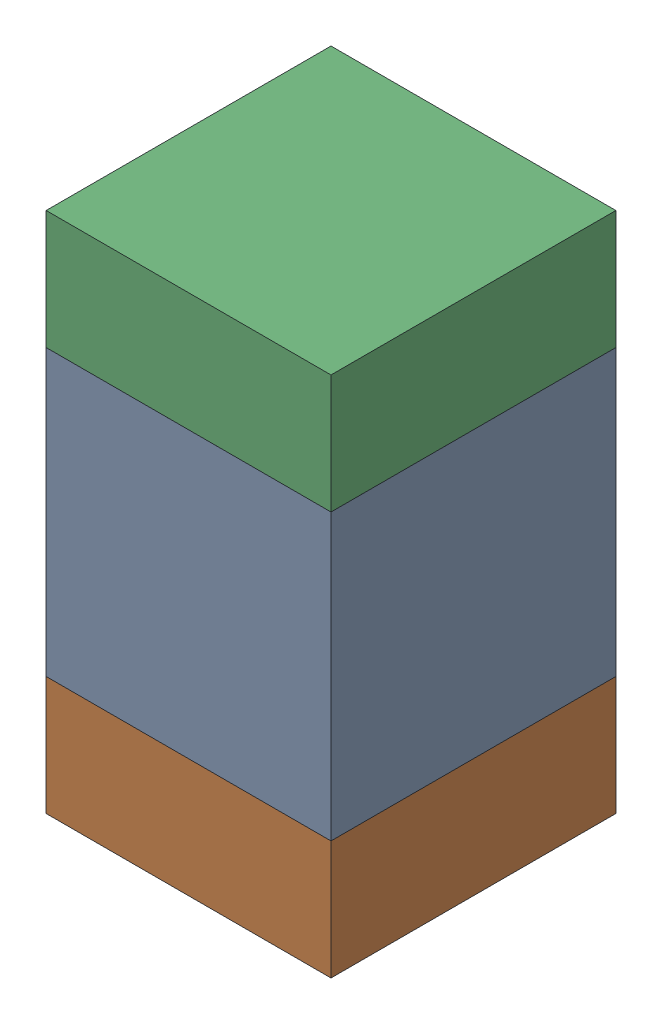
SolidWorks assembly C114_1PCB, configuration Default. Lengths in mm.
Overall size (0.6 1.1 0.6).
6 component instances, 2 part files, 0 mates.
Components (placement in the parent):
- 761606048-1: 761606048 [Default] at (116.1 121 0) size (0.6 0.6 0.6)
  - Extruded_9-1: Extruded_9 [Default] at origin size (0.6 0.6 0.6)
- 854785296-1: 854785296 [Default] at (116.1 120.575 0) size (0.6 0.25 0.6)
  - Extruded_10-1: Extruded_10 [Default] at origin size (0.6 0.25 0.6)
- 854785296-2: 854785296 [Default] at (116.1 121.425 0) size (0.6 0.25 0.6)
  - Extruded_10-1: Extruded_10 [Default] at origin size (0.6 0.25 0.6)
